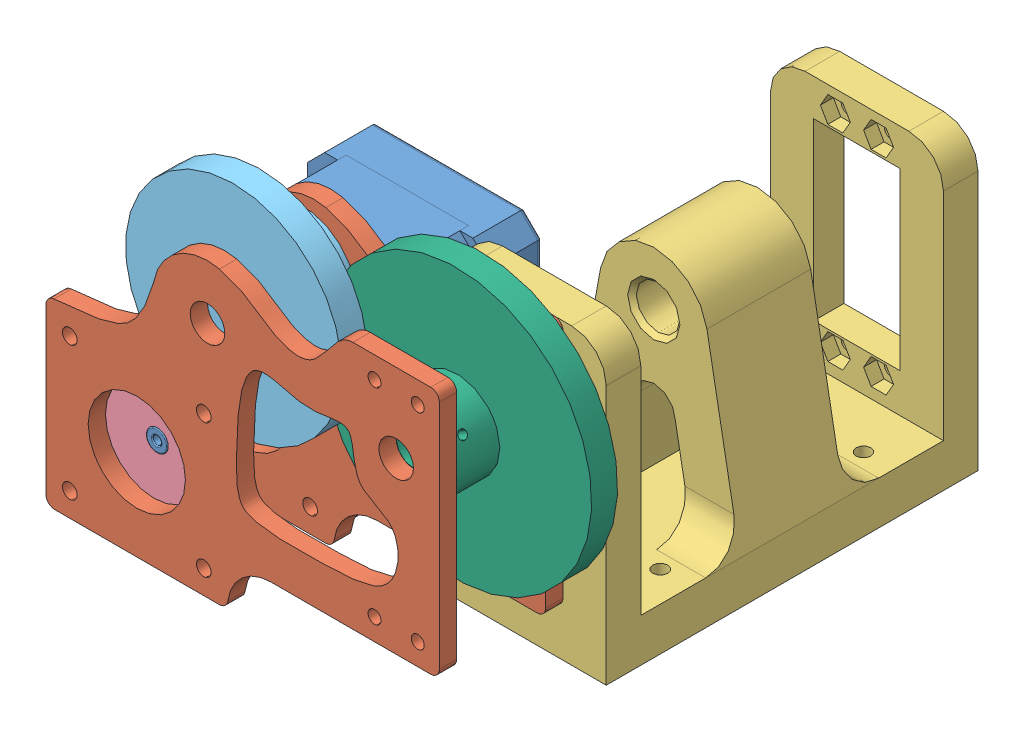
SolidWorks assembly Сборка2 - Новое основание, configuration Default. Lengths in mm.
Overall size (124.37 93.12 114.6).
9 component instances, 7 part files, 17 mates.
Components (placement in the parent):
- Morot  Nema 17 model 17HS8401-1: Morot  Nema 17 model 17HS8401 [По умолчанию] at (53.5117 33.7971 3.7034) size (42.3 42.3 68.65)
- Плита_1-1: Плита_1 [Default] at (103.1162 67.1642 47.7034) size (91 68.07 4)
- Shoulder Base-1: Shoulder Base [По умолчанию] at (103.1162 27.4142 4.7034) x (0 0 -1) z (1 0 0) size (86 68 40)
- z1-1: z1 [Default] at (43.1162 38.4142 71.5196) x (-0.893085 -0.449887 0) z (0 0 -1) size (25 25 16)
- z2-z3-1: z2-z3 [Default] at (59.4767 72.3793 64.265) x (0.859563 0.511029 0) z (0 0 1) size (50 50 16)
- z4-1: z4 [Default] at (103.1162 67.1642 56.3034) x (0.839204 0.543816 0) z (0 0 1) size (62.5 62.5 16)
- Плита_1-2: Плита_1 [Default] at (103.1162 67.1642 72.3034) size (91 68.07 4)
- flat washer regular_am-1: flat washer regular_am [B18.22M - Plain washer, 8 mm, regular] at (103.1162 67.1642 54.0034) x (0 0 -1) z (1 0 0) size (2.3 25.4 25.4)
- flat washer regular_am-2: flat washer regular_am [B18.22M - Plain washer, 8 mm, regular] at (103.1162 67.1642 51.7034) x (0 0 -1) z (0.70288 -0.711308 0) size (2.3 25.4 25.4)
Mates (geometry in assembly coordinates):
- Концентричный2: concentric anti-aligned: cylinder of Плита_1-1 through (98.1162 80.4142 51.7034) axis (0 0 -1) radius 1.5; cylinder of Shoulder Base-1 through (98.1162 80.4142 -5.4657) axis (0 0 1) radius 1.7
- Концентричный3: concentric anti-aligned: cylinder of Плита_1-1 through (108.1162 32.9142 51.7034) axis (0 0 -1) radius 1.5; cylinder of Shoulder Base-1 through (108.1162 32.9142 -5.4657) axis (0 0 1) radius 1.7
- Концентричный4: concentric anti-aligned: cylinder of Morot  Nema 17 model 17HS8401-1 through (43.1162 38.4142 71.7034) axis (0 0 -1) radius 2.5; cylinder of z1-1 through (43.1162 38.4142 63.5196) axis (0 0 1) radius 2.5
- Совпадение1: coincident anti-aligned: plane of Morot  Nema 17 model 17HS8401-1 through (43.1162 38.4142 47.7034) normal (0 0 1); plane of Плита_1-1 through (103.1162 67.1642 47.7034) normal (0 0 -1)
- Концентричный5: concentric anti-aligned: cylinder of Morot  Nema 17 model 17HS8401-1 through (27.6162 53.9142 43.2034) axis (0 0 1) radius 1.5; cylinder of Плита_1-1 through (27.6162 53.9142 51.7034) axis (0 0 -1) radius 1.7
- Концентричный6: concentric anti-aligned: cylinder of Morot  Nema 17 model 17HS8401-1 through (58.6162 22.9142 43.2034) axis (0 0 1) radius 1.5; cylinder of Плита_1-1 through (58.6162 22.9142 51.7034) axis (0 0 -1) radius 1.7
- Концентричный7: concentric aligned: cylinder of Плита_1-1 through (59.4767 72.3793 51.7034) axis (0 0 -1) radius 4; cylinder of z2-z3-1 through (59.4767 72.3793 70.265) axis (0 0 -1) radius 4
- Концентричный8: concentric aligned: cylinder of Плита_1-1 through (103.1162 67.1642 51.7034) axis (0 0 -1) radius 4; cylinder of z4-1 through (103.1162 67.1642 62.3034) axis (0 0 -1) radius 4
- Концентричный9: concentric anti-aligned: cylinder of Morot  Nema 17 model 17HS8401-1 through (27.6162 53.9142 43.2034) axis (0 0 1) radius 1.5; cylinder of Плита_1-2 through (27.6162 53.9142 76.3034) axis (0 0 -1) radius 1.7
- Концентричный10: concentric anti-aligned: cylinder of Morot  Nema 17 model 17HS8401-1 through (58.6162 22.9142 43.2034) axis (0 0 1) radius 1.5; cylinder of Плита_1-2 through (58.6162 22.9142 76.3034) axis (0 0 -1) radius 1.7
- Совпадение3: coincident anti-aligned: plane of Плита_1-1 through (103.1162 67.1642 47.7034) normal (0 0 -1); plane of Shoulder Base-1 through (123.1162 27.4142 47.7034) normal (0 0 1)
- Концентричный11: concentric anti-aligned: cylinder of Плита_1-1 through (103.1162 67.1642 51.7034) axis (0 0 -1) radius 4; cylinder of flat washer regular_am-1 through (103.1162 67.1642 88.9284) axis (0 0 1) radius 4.56
- Концентричный12: concentric anti-aligned: cylinder of Плита_1-1 through (103.1162 67.1642 51.7034) axis (0 0 -1) radius 4; cylinder of flat washer regular_am-2 through (103.1162 67.1642 86.6284) axis (0 0 1) radius 4.56
- Совпадение4: coincident anti-aligned: plane of z4-1 through (103.1162 67.1642 56.3034) normal (0 0 -1); plane of flat washer regular_am-1 through (103.1162 79.8642 56.3034) normal (0 0 1)
- Совпадение8: coincident anti-aligned: plane of flat washer regular_am-1 through (103.1162 71.7242 54.0034) normal (0 0 -1); plane of flat washer regular_am-2 through (112.1498 76.0908 54.0034) normal (0 0 1)
- Совпадение9: coincident anti-aligned: plane of Плита_1-1 through (103.1162 67.1642 51.7034) normal (0 0 1); plane of flat washer regular_am-2 through (106.3597 70.3694 51.7034) normal (0 0 -1)
- Совпадение10: coincident anti-aligned: plane of z4-1 through (103.1162 67.1642 72.3034) normal (0 0 1); plane of Плита_1-2 through (103.1162 67.1642 72.3034) normal (0 0 -1)
